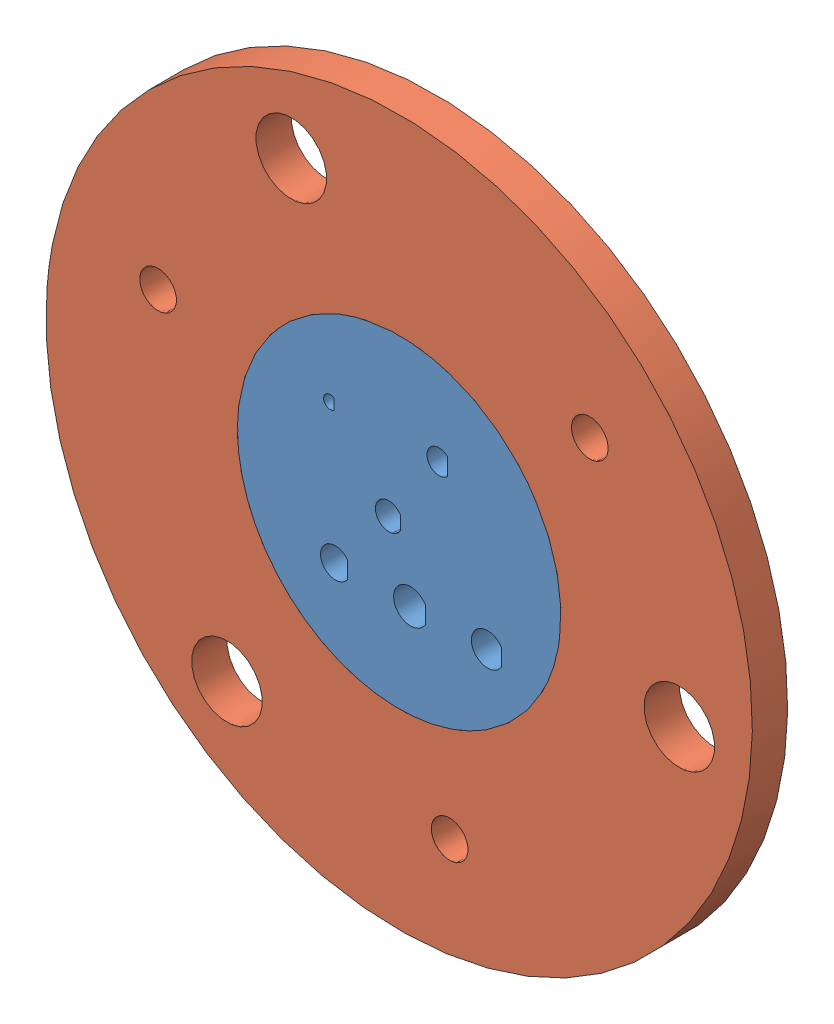
SolidWorks assembly Assem1, configuration Default. Lengths in mm.
Overall size (142.59 142.59 6.35).
2 component instances, 2 part files, 1 mates.
Components (placement in the parent):
- D-test-1: D-test [Default] at (41.6808 153.525 30.6742) size (58.17 58.17 6.35)
- CenteringCylinderStack-1: CenteringCylinderStack [Default] at (65.1387 153.525 37.0242) x (0.131414 0.991328 0) z (-0.991328 0.131414 0) size (127 6.35 127)
Mates (geometry in assembly coordinates):
- Coincident5: coincident aligned: plane of D-test-1 through (41.6808 153.525 37.0242) normal (0 0 1); plane of CenteringCylinderStack-1
